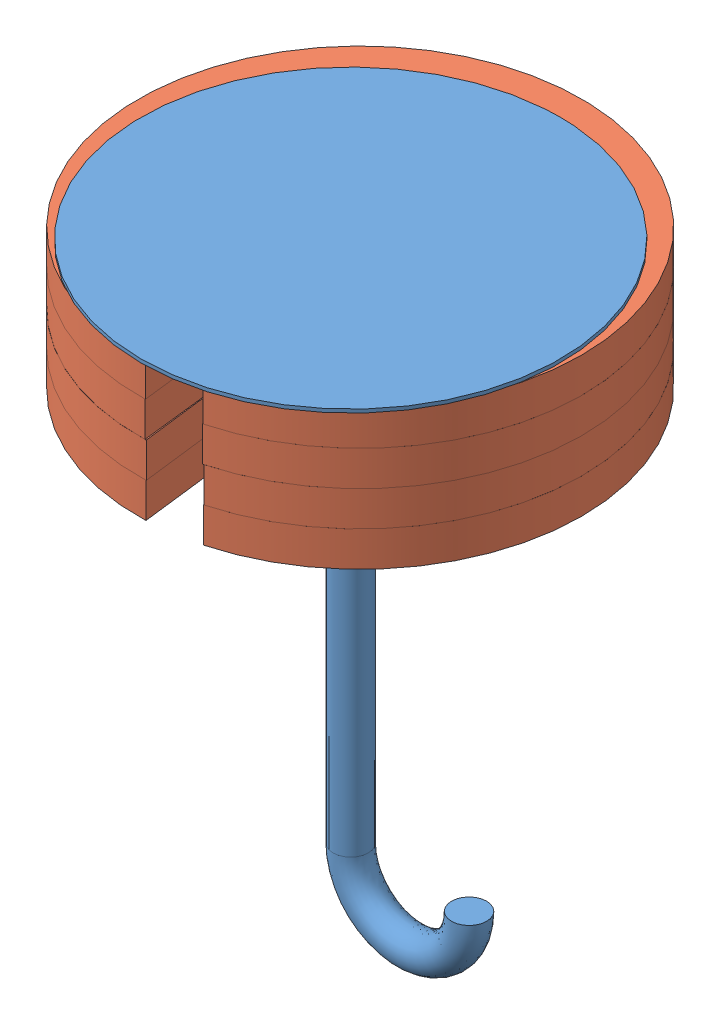
SolidWorks assembly weight plate and umbrella assem, configuration Default. Lengths in mm.
Overall size (141.43 171.97 141.23).
5 component instances, 2 part files, 11 mates.
Components (placement in the parent):
- umbrella-1: umbrella [Default] at (189.9035 74.7407 90.4662) size (120 171.97 120)
- weight umbrella-1: weight umbrella [Default] at (182.4991 132.1144 85.3731) x (0.993128 0 -0.117032) z (0 1 0) size (127 126.76 10)
- weight umbrella-2: weight umbrella [Default] at (182.5077 122.1144 85.3691) x (0.993324 0 -0.115355) z (0 1 0) size (127 126.76 10)
- weight umbrella-3: weight umbrella [Default] at (182.4775 112.1144 85.3833) x (0.992623 0 -0.121238) z (0 1 0) size (127 126.76 10)
- weight umbrella-4: weight umbrella [Default] at (182.4859 102.1144 85.3793) x (0.992822 0 -0.119599) z (0 1 0) size (127 126.76 10)
Mates (geometry in assembly coordinates):
- Parallel2: parallel anti-aligned: plane of umbrella-1 through (184.8858 142.1144 90.4715) normal (0 -1 0); plane of weight umbrella-1 through (182.4991 142.1144 85.3731) normal (0 1 0)
- Concentric1: concentric anti-aligned: cylinder of umbrella-1 through (184.8858 143.1144 90.4715) axis (0 -1 0) radius 5.0176; cylinder of weight umbrella-1 through (184.8858 132.1144 90.4715) axis (0 1 0) radius 7.2431
- Coincident3: coincident anti-aligned: plane of umbrella-1 through (184.8858 142.1144 90.4715) normal (0 -1 0); plane of weight umbrella-1 through (182.4991 142.1144 85.3731) normal (0 1 0)
- Parallel3: parallel anti-aligned: plane of weight umbrella-1 through (182.4991 132.1144 85.3731) normal (0 -1 0); plane of weight umbrella-2 through (182.5077 132.1144 85.3691) normal (0 1 0)
- Concentric2: concentric anti-aligned: cylinder of umbrella-1 through (184.8858 143.1144 90.4715) axis (0 -1 0) radius 5.0176; cylinder of weight umbrella-2 through (184.8858 122.1144 90.4715) axis (0 1 0) radius 7.2431
- Coincident5: coincident anti-aligned: plane of weight umbrella-1 through (182.4991 132.1144 85.3731) normal (0 -1 0); plane of weight umbrella-2 through (182.5077 132.1144 85.3691) normal (0 1 0)
- Parallel4: parallel anti-aligned: plane of weight umbrella-2 through (182.5077 122.1144 85.3691) normal (0 -1 0); plane of weight umbrella-3 through (182.4775 122.1144 85.3833) normal (0 1 0)
- Concentric3: concentric anti-aligned: cylinder of umbrella-1 through (184.8858 143.1144 90.4715) axis (0 -1 0) radius 5.0176; cylinder of weight umbrella-3 through (184.8858 112.1144 90.4715) axis (0 1 0) radius 7.2431
- Coincident7: coincident anti-aligned: plane of weight umbrella-2 through (182.5077 122.1144 85.3691) normal (0 -1 0); plane of weight umbrella-3 through (182.4775 122.1144 85.3833) normal (0 1 0)
- Concentric4: concentric anti-aligned: cylinder of umbrella-1 through (184.8858 143.1144 90.4715) axis (0 -1 0) radius 5.0176; cylinder of weight umbrella-4 through (184.8858 102.1144 90.4715) axis (0 1 0) radius 7.2431
- Coincident8: coincident anti-aligned: plane of weight umbrella-3 through (182.4775 112.1144 85.3833) normal (0 -1 0); plane of weight umbrella-4 through (182.4859 112.1144 85.3793) normal (0 1 0)
